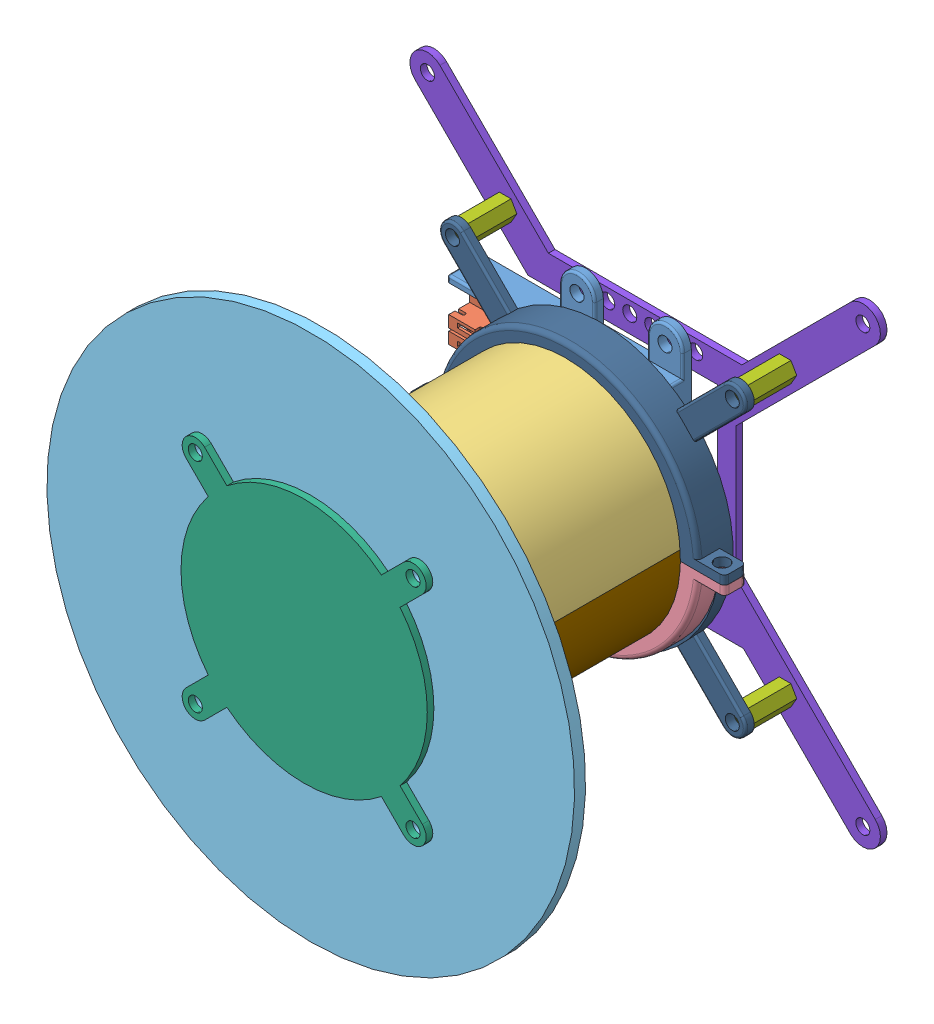
SolidWorks assembly Camera Module, configuration Default. Lengths in mm.
Overall size (120 120 79).
14 component instances, 10 part files, 16 mates.
Components (placement in the parent):
- DCam 2-1: DCam 2 [Default] at (30.7383 40.0459 57.322) x (0 1 0) z (0 0 1) size (58 47.5 8)
- Open MV-1: Open MV [Default] at (-13.6637 57.818 60.2844) x (0.000672 -1 0) z (0 0 1) size (35.56 48.81 35.24)
- 镜筒-1: 镜筒 [默认] at (21.7049 41.0459 60.322) x (1 0 0) z (0 -1 0) size (52 60 52)
- camera lock-2: camera lock [Default] at (21.7717 40.0459 70.322) x (0 -1 0) z (0 0 1) size (29.08 72 5.06)
- NH Top Cover V5-1: NH Top Cover V5 [Default] at (21.7049 41.0459 135.322) x (1 0 0) z (0 1 0) size (120 8 120)
- camera lock-3: camera lock [Default] at (21.7383 41.0459 130.572) x (0 1 0) z (0 0 -1) size (29.08 72 5.06)
- Mirror Adaptor-1: Mirror Adaptor [Default] at (21.7049 41.0459 133.322) x (1 0 0) z (0 -1 0) size (56 10.5 56)
- 10mm Standoff-1: 10mm Standoff [默认] at (53.5581 8.2261 57.322) x (1 0 0) z (0 -1 0) size (5.31 10 4.6)
- 10mm Standoff-2: 10mm Standoff [默认] at (-10.0815 8.2261 57.322) x (1 0 0) z (0 -1 0) size (5.31 10 4.6)
- 10mm Standoff-3: 10mm Standoff [默认] at (53.5581 71.8657 57.322) x (1 0 0) z (0 -1 0) size (5.31 10 4.6)
- 10mm Standoff-4: 10mm Standoff [默认] at (-10.0815 71.8657 57.322) x (1 0 0) z (0 -1 0) size (5.31 10 4.6)
- Open Cam 1 - V2-1: Open Cam 1 - V2 [Default] at (21.7383 40.0459 55.822) size (106.99 106.99 1.5)
- Tube-1: Tube [Default] at (21.7383 40.0459 70.322) x (0 1 0) z (1 0 0) size (52 60 52)
- Open Cam 2-2: Open Cam 2 [Default] at (21.7383 40.0459 68.322) size (72 69.64 8.06)
Mates (geometry in assembly coordinates):
- Lock1: lock: unknown of DCam 2-1; unknown of Open MV-1
- Concentric28: concentric anti-aligned: cylinder of 镜筒-1 through (21.7049 41.0459 130.322) axis (0 0 -1) radius 26; cylinder of NH Top Cover V5-1 through (21.7049 41.0459 122.322) axis (0 0 1) radius 24
- Coincident11: coincident anti-aligned: plane of NH Top Cover V5-1 through (21.7049 41.0459 131.322) normal (0 1 0); plane of camera lock-3 through (57.7383 41.0459 130.572) normal (0 -1 0)
- Concentric29: concentric aligned: cylinder of NH Top Cover V5-1 through (54.7049 37.0459 128.072) axis (0 1 0) radius 1.6; cylinder of camera lock-3 through (54.7049 41.0459 128.072) axis (0 1 0) radius 1.6
- Parallel7: parallel aligned: cylinder of NH Top Cover V5-1 through (-11.2951 37.0459 128.072) axis (0 1 0) radius 1.6; cylinder of camera lock-3 through (-11.2283 41.0459 128.072) axis (0 1 0) radius 1.6
- Coincident12: coincident anti-aligned: plane of NH Top Cover V5-1 through (21.7049 41.0459 133.322) normal (0 0 1); plane of Mirror Adaptor-1 through (0.4917 19.8327 133.322) normal (0 0 -1)
- Concentric31: concentric aligned: cylinder of NH Top Cover V5-1 through (-3.0438 16.2971 122.322) axis (0 0 1) radius 1.6; cylinder of Mirror Adaptor-1 through (-3.0438 16.2971 116.243) axis (0 0 1) radius 1.6
- Concentric32: concentric aligned: cylinder of NH Top Cover V5-1 through (46.4537 65.7946 122.322) axis (0 0 1) radius 1.6; cylinder of Mirror Adaptor-1 through (46.4537 65.7946 116.243) axis (0 0 1) radius 1.6
- Concentric41: concentric anti-aligned: cylinder of 10mm Standoff-3 through (53.5581 71.8657 62.322) axis (0 0 -1) radius 1.5; cylinder of Open Cam 1 - V2-1 through (53.5581 71.8657 47.322) axis (0 0 1) radius 1.6
- Coincident20: coincident anti-aligned: plane of 10mm Standoff-4 through (-10.0815 71.8657 57.322) normal (0 0 -1); plane of Open Cam 1 - V2-1 through (21.7383 40.0459 57.322) normal (0 0 1)
- Concentric42: concentric anti-aligned: cylinder of 10mm Standoff-1 through (53.5581 8.2261 62.322) axis (0 0 -1) radius 1.5; cylinder of Open Cam 1 - V2-1 through (53.5581 8.2261 47.322) axis (0 0 1) radius 1.6
- Concentric44: concentric anti-aligned: cylinder of camera lock-3 through (21.7383 40.0459 125.572) axis (0 0 1) radius 26.0192; cylinder of Tube-1 through (21.7383 40.0459 130.322) axis (0 0 -1) radius 26
- Concentric45: concentric aligned: cylinder of 10mm Standoff-2 through (-10.0815 8.2261 62.322) axis (0 0 -1) radius 1.5; cylinder of Open Cam 2-2 through (-10.0815 8.2261 69.322) axis (0 0 -1) radius 1.6
- Coincident21: coincident anti-aligned: plane of 10mm Standoff-1 through (53.5581 8.2261 67.322) normal (0 0 1); plane of Open Cam 2-2 through (21.7383 40.0459 67.322) normal (0 0 -1)
- Concentric46: concentric aligned: cylinder of 10mm Standoff-4 through (-10.0815 71.8657 62.322) axis (0 0 -1) radius 1.5; cylinder of Open Cam 2-2 through (-10.0815 71.8657 69.322) axis (0 0 -1) radius 1.6
- Concentric47: concentric aligned: cylinder of Tube-1 through (21.7383 40.0459 130.322) axis (0 0 -1) radius 26; cylinder of Open Cam 2-2 through (21.7383 40.0459 75.322) axis (0 0 -1) radius 26
